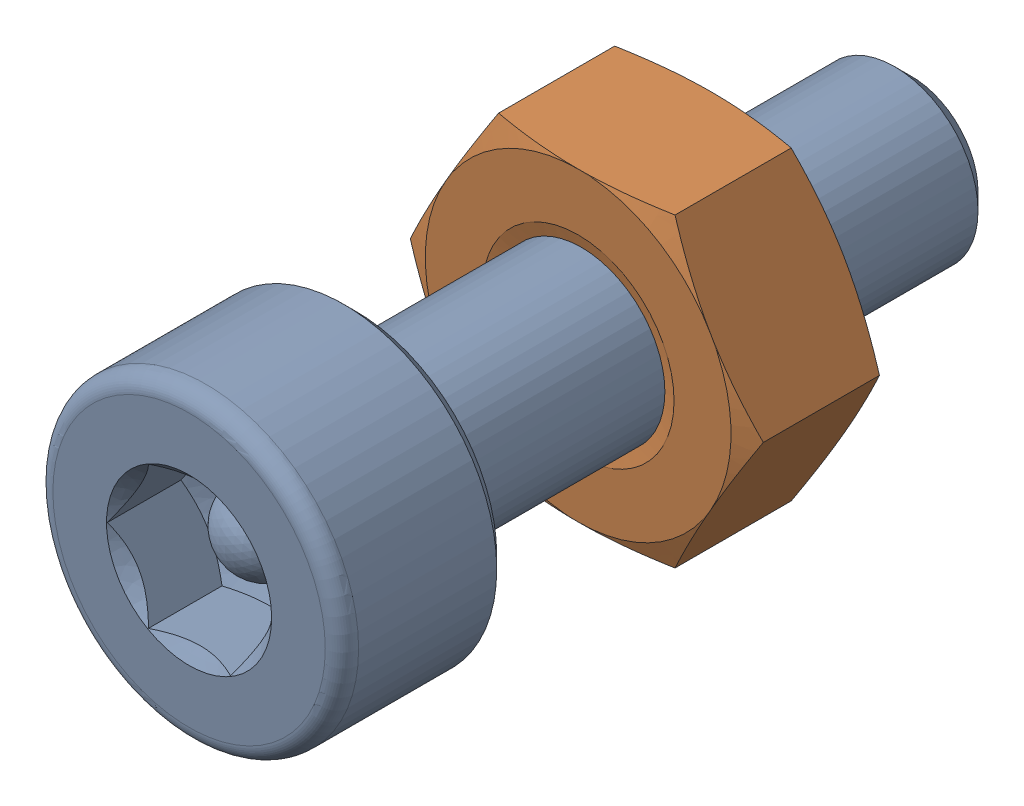
SolidWorks assembly Screw and Nut M3x010_022-1, configuration Varsayılan. Lengths in mm.
Overall size (6.35 5.5 13.14).
2 component instances, 2 part files, 0 mates.
Components (placement in the parent):
- M3x10-Screw021-1-1: M3x10-Screw021-1 [Varsayılan] at origin size (5.5 5.5 13.14)
- M3-Nut053-1-1: M3-Nut053-1 [Varsayılan] at (0 0 -4) x (-1 0 0) z (0 0 -1) size (6.35 5.5 2.4)
